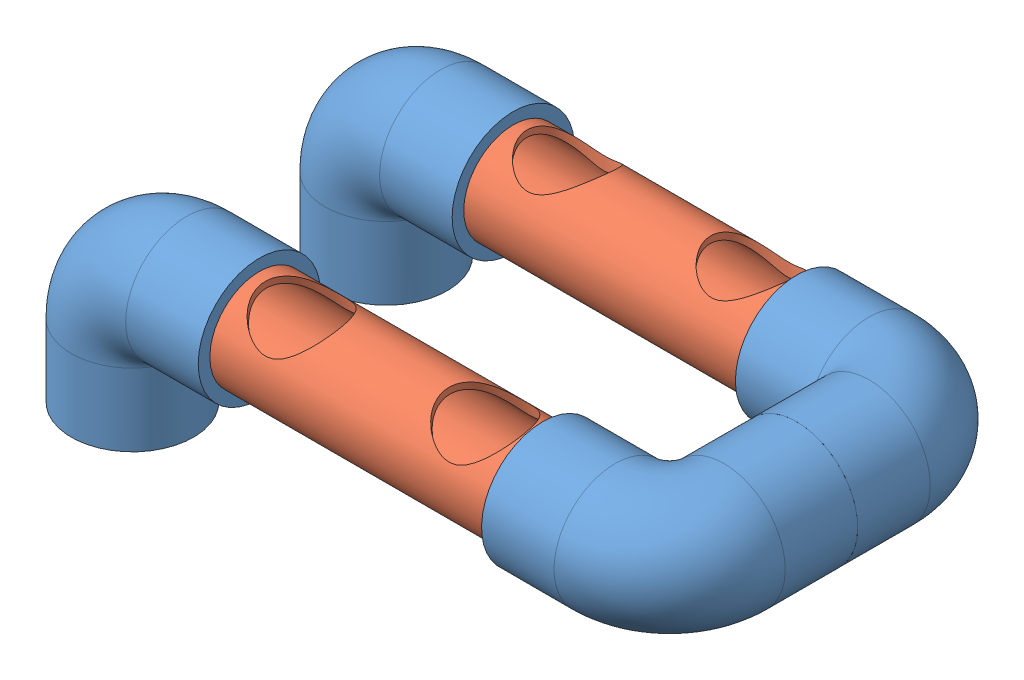
SolidWorks assembly Assem1, configuration Default. Lengths in mm.
Overall size (327.44 96.36 184.4).
7 component instances, 2 part files, 10 mates.
Components (placement in the parent):
- 1.5in Elbow-1: 1.5in Elbow [1.5in Elbow] at (44.134 370.8447 451.0537) x (-1 0 0) z (0 0 1) size (92.2 92.2 59.94)
- 1.5in pipe-1: 1.5in pipe [30cm] at (280.804 370.8447 451.0537) x (0 -0.182542 0.983198) z (-1 0 0) size (48.56 48.56 210)
- 1.5in Elbow-2: 1.5in Elbow [1.5in Elbow] at (307.474 370.8447 451.0537) x (1 0 0) z (0 1 0) size (92.2 92.2 59.94)
- 1.5in pipe-2: 1.5in pipe [71.12cm] at (307.474 370.8447 424.3837) x (0.625868 0.779929 0) z (0 0 -1) size (48.56 48.56 71.12)
- 1.5in Elbow-3: 1.5in Elbow [1.5in Elbow] at (307.474 370.8447 326.5937) x (1 0 0) z (0 -1 0) size (92.2 92.2 59.94)
- 1.5in pipe-3: 1.5in pipe [30cm] at (280.804 370.8447 326.5937) x (0 0.100903 0.994896) z (-1 0 0) size (48.56 48.56 210)
- 1.5in Elbow-4: 1.5in Elbow [1.5in Elbow] at (44.134 370.8447 326.5937) x (-1 0 0) z (0 0 1) size (92.2 92.2 59.94)
Mates (geometry in assembly coordinates):
- Concentric5: concentric anti-aligned: cone of 1.5in Elbow-1 through (70.804 370.8447 451.0537) axis (-1 0 0); cylinder of 1.5in pipe-1 through (70.804 370.8447 451.0537) axis (1 0 0) radius 24.28
- Concentric6: concentric aligned: cylinder of 1.5in pipe-1 through (70.804 370.8447 451.0537) axis (1 0 0) radius 24.28; cone of 1.5in Elbow-2 through (280.804 370.8447 451.0537) axis (1 0 0)
- Coincident13: coincident anti-aligned: plane of 1.5in pipe-1 through (280.804 370.8447 451.0537) normal (1 0 0); plane of 1.5in Elbow-2 through (280.804 370.8447 451.0537) normal (-1 0 0)
- Concentric7: concentric aligned: cone of 1.5in Elbow-2 through (307.474 370.8447 388.8237) axis (0 0 1); cylinder of 1.5in pipe-2 through (307.474 370.8447 353.2637) axis (0 0 1) radius 24.28
- Coincident15: coincident anti-aligned: plane of 1.5in Elbow-2 through (307.474 370.8447 424.3837) normal (0 0 -1); plane of 1.5in pipe-2 through (307.474 370.8447 424.3837) normal (0 0 1)
- Concentric8: concentric anti-aligned: cylinder of 1.5in pipe-2 through (307.474 370.8447 353.2637) axis (0 0 1) radius 24.28; cone of 1.5in Elbow-3 through (307.474 370.8447 388.8237) axis (0 0 -1)
- Coincident16: coincident anti-aligned: plane of 1.5in pipe-2 through (307.474 370.8447 353.2637) normal (0 0 -1); plane of 1.5in Elbow-3 through (307.474 370.8447 353.2637) normal (0 0 1)
- Concentric91: concentric aligned: cone of 1.5in Elbow-3 through (280.804 370.8447 326.5937) axis (1 0 0); cylinder of 1.5in pipe-3 through (70.804 370.8447 326.5937) axis (1 0 0) radius 24.28
- Coincident18: coincident anti-aligned: plane of 1.5in Elbow-3 through (280.804 370.8447 326.5937) normal (-1 0 0); plane of 1.5in pipe-3 through (280.804 370.8447 326.5937) normal (1 0 0)
- Concentric10: concentric anti-aligned: cylinder of 1.5in pipe-3 through (70.804 370.8447 326.5937) axis (1 0 0) radius 24.28; cone of 1.5in Elbow-4 through (70.804 370.8447 326.5937) axis (-1 0 0)
